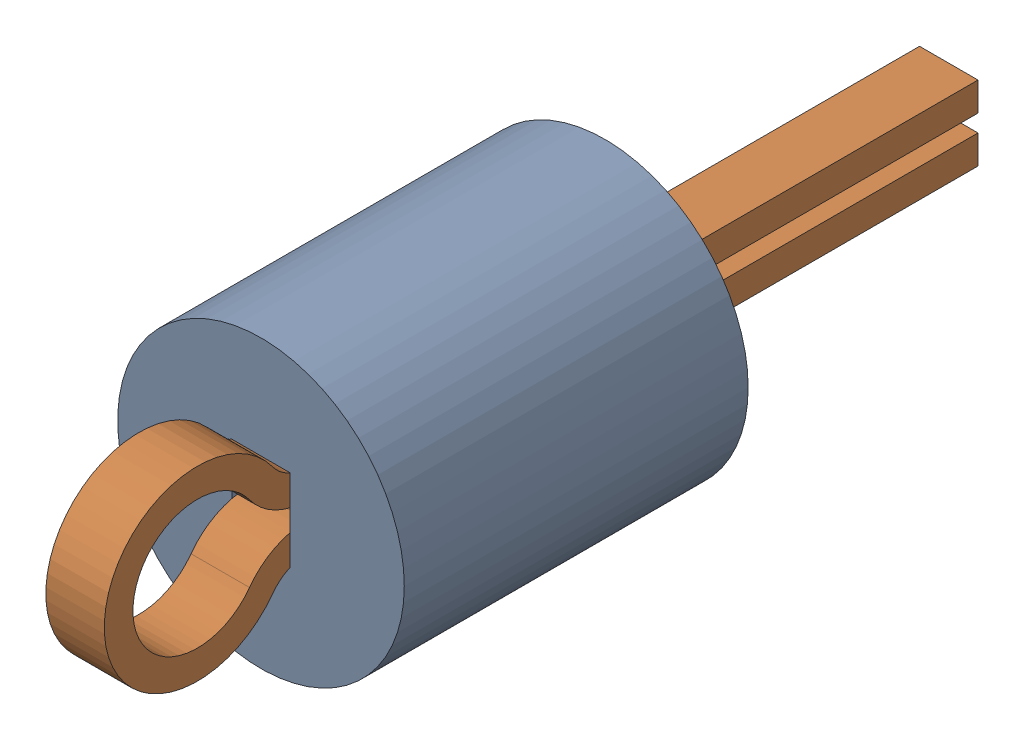
SolidWorks assembly TP2, configuration Default. Lengths in mm.
Overall size (2.5 2.5 7.62).
3 component instances, 2 part files, 0 mates.
Components (placement in the parent):
- Keystone_5002-1: Keystone_5002 [Default] at (24.8875 31.7529 0) size (2.5 2.5 7.62)
  - Keystone5002_white-1: Keystone5002_white [Default] at origin size (2.5 2.5 3)
  - Keystone500x_wire-1: Keystone500x_wire [Default] at origin size (0.51 1.62 7.62)
